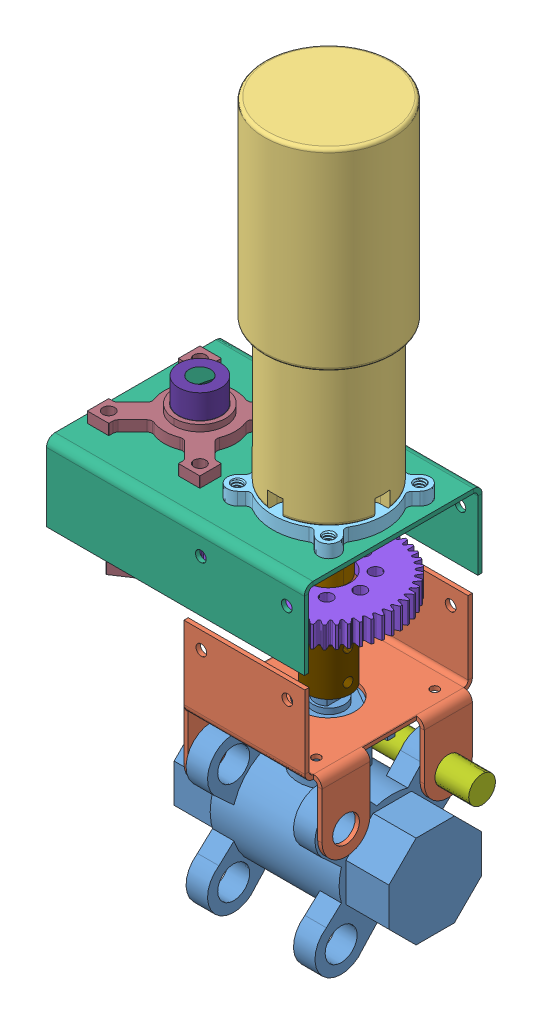
SolidWorks assembly V3 Assembly, configuration Default. Lengths in mm.
Overall size (161.11 207.52 132.19).
34 component instances, 18 part files, 39 mates.
Components (placement in the parent):
- Sharpe 39036-1: Sharpe 39036 [Default] at (-57.1499 -3.3368 16.1541) size (63.5 64.02 45.72)
- Base-sheetmetal-2: Base-sheetmetal [Default] at (-38.0085 26.79 16.1541) x (1 0 0) z (0 0 -1) size (40.82 46.26 49.53)
- Motor_12VDC_638263-1: Motor_12VDC_638263 [Default] at (-38.0997 79.427 15.8703) x (0 0 1) z (1 0 0) size (38 101.9 38)
- Motor_12VDC_638263_shaft-1: Motor_12VDC_638263_shaft [Default] at (-38.0999 79.427 15.8701) x (-0.162768 0 0.986664) z (0.986664 0 0.162768) size (6 16.2 6)
- 555174-1: 555174 [Default] at (-38.0999 82.427 15.8701) x (0 0 -1) z (-1 0 0) size (33.02 4.05 33.02)
- Top-sheetmetal-V3-1: Top-sheetmetal-V3 [Default] at (-57.1499 77.347 15.8701) x (-1 0 0) z (0 0 1) size (76.2 22.86 52.58)
- Sharpe 39036 Bolt-1: Sharpe 39036 Bolt [Default] at (-63.4999 11.7762 1.0411) size (55.88 14.66 12.7)
- 615190 - spur gear-1: 615190 - spur gear [Default] at (-38.0999 60.052 15.8701) x (-0.674102 0 -0.738638) z (0 -1 0) size (39.69 39.69 6.35)
- 625106 assembly.STEP-1: 625106 assembly.STEP [Default] at (-27.8125 48.8438 87.7833) x (-0.17668 0 0.984268) z (-0.984268 0 -0.17668) size (10.67 19.05 10.67)
  - 625106.STEP-1: 625106.STEP [Default] at (-68.9644 10.3754 22.8311) size (10.67 19.05 10.67)
  - 632134_91375A436.STEP-1: 632134_91375A436.STEP [Default] at (-68.9644 13.8044 26.9749) x (-0.895963 0.444129 0) z (0 0 1) size (4.83 4.83 3.18)
  - 632134_91375A436.STEP-2: 632134_91375A436.STEP [Default] at (-68.9644 25.9964 26.9749) x (-0.28947 0.957187 0) z (0 0 1) size (4.83 4.83 3.18)
- 545588 assembly-1: 545588 assembly [Default] at (50.7468 28.5299 -12.9854) x (0.998958 0 0.045634) z (-0.045634 0 0.998958) size (100.53 31.16 84.78)
  - 545588 assembly.STEP-1: 545588 assembly.STEP [Default] at origin size (100.53 31.16 84.78)
    - 545588.STEP-1: 545588.STEP [Default] at (-87.4372 18.8221 32.8798) size (20.57 9.53 26.29)
    - 632110_90128A121.STEP-1: 632110_90128A121.STEP [Default] at (-120.7747 24.8546 20.3068) x (0 0 1) z (-1 0 0) size (5.61 5.61 13.03)
- 535110 assembly - Pillow-1: 535110 assembly - Pillow [Default] at (-82.8272 63.3692 -12.4397) size (33.27 5.08 33.27)
  - 535110 assembly - Pillow.STEP-1: 535110 assembly - Pillow.STEP [Default] at origin size (33.27 5.08 33.27)
    - 535110.STEP-1: 535110.STEP [Default] at (6.6273 15.2478 28.3097) size (33.27 5.08 33.27)
    - 535020.STEP-1: 535020.STEP [Default] at (6.6273 17.9338 28.3097) size (12.7 4.76 12.7)
- D-shaft-2in-2: D-shaft-2in [Default] at (-76.1999 40.042 15.8701) x (0.971835 0 0.23566) z (-0.23566 0 0.971835) size (5.71 50.8 6.35)
- D-shaft-125in-1: D-shaft-125in [Default] at (-38.0999 37.827 15.8701) size (5.71 25.4 6.35)
- Set collar .25in-1: Set collar .25in [Default] at (-76.1999 83.697 15.8701) size (12.48 7.15 12.48)
- 545588 assembly-3: 545588 assembly [Default] at (-62.9007 85.224 -76.5934) x (-0.215135 0 -0.976584) z (-0.976584 0 0.215135) size (100.53 31.16 84.78)
  - 545588 assembly.STEP-1: 545588 assembly.STEP [Default] at origin size (100.53 31.16 84.78)
    - 545588.STEP-1: 545588.STEP [Default] at (-87.4372 18.8221 32.8798) size (20.57 9.53 26.29)
    - 632110_90128A121.STEP-1: 632110_90128A121.STEP [Default] at (-120.7747 24.8546 20.3068) x (0 0 1) z (-1 0 0) size (5.61 5.61 13.03)
- 615190 - spur gear-3: 615190 - spur gear [Default] at (-76.1999 53.702 15.8701) x (0.215135 0 0.976584) z (0 1 0) size (39.69 39.69 6.35)
- shaft-adapter-2: shaft-adapter [Default] at (-38.0999 47.352 15.8701) x (-0.995854 0 -0.090967) z (0.090967 0 -0.995854) size (12.7 15.88 12.7)
- 535110 assembly - Pillow-2: 535110 assembly - Pillow [Default] at (-66.1246 67.5148 43.1437) x (0.834361 0 -0.551218) z (-0.551218 0 -0.834361) size (33.27 5.08 33.27)
  - 535110 assembly - Pillow.STEP-1: 535110 assembly - Pillow.STEP [Default] at origin size (33.27 5.08 33.27)
    - 535110.STEP-1: 535110.STEP [Default] at (6.6273 15.2478 28.3097) size (33.27 5.08 33.27)
    - 535020.STEP-1: 535020.STEP [Default] at (6.6273 17.9338 28.3097) size (12.7 4.76 12.7)
- Set collar .25in-2: Set collar .25in [Default] at (-76.1999 40.042 15.8701) size (12.48 7.15 12.48)
Mates (geometry in assembly coordinates):
- Concentric3: concentric: cylinder of Sharpe 39036-1 through (-19.0499 11.7762 31.2671) axis (-1 0 0) radius 4.7307; circle of Base-sheetmetal-2
- Coincident5: coincident: plane of Sharpe 39036-1 through (-57.1499 -3.3368 16.1541) normal (-1 0 0); plane of Base-sheetmetal-2 through (-57.1499 46.3837 16.1541) normal (1 0 0)
- Concentric4: concentric: circle of Sharpe 39036-1; circle of Base-sheetmetal-2
- Coincident6: coincident: plane of Motor_12VDC_638263-1 through (-38.0997 79.427 15.8703) normal (0 -1 0); plane of Motor_12VDC_638263_shaft-1 through (-38.0999 79.427 15.8701) normal (0 1 0)
- Concentric5: concentric: circle of Motor_12VDC_638263-1; circle of Motor_12VDC_638263_shaft-1
- Concentric6: concentric: cylinder of Sharpe 39036-1 through (-38.0999 23.222 15.8701) axis (0 -1 0) radius 9.0805; cylinder of Motor_12VDC_638263_shaft-1 through (-38.0999 63.227 15.8701) axis (0 1 0) radius 3
- Coincident12: coincident: plane of Motor_12VDC_638263-1 through (-38.0997 82.427 15.8703) normal (0 -1 0); plane of 555174-1 through (-38.0999 82.427 15.8701) normal (0 1 0)
- Concentric7: concentric: cylinder of Motor_12VDC_638263-1 through (-38.0997 124.227 15.8703) axis (0 -1 0) radius 16; cylinder of 555174-1 through (-38.0999 82.427 15.8701) axis (0 1 0) radius 10.033
- Coincident13: coincident: circle of Motor_12VDC_638263-1; cylinder of 555174-1 through (-47.292 81.157 6.6779) axis (0 -1 0) radius 1.5
- Coincident17: coincident: plane of Base-sheetmetal-2 through (-58.4199 46.3837 16.1541) normal (-1 0 0); plane of Sharpe 39036 Bolt-1 through (-58.4199 11.7762 1.0411) normal (1 0 0)
- Concentric15: concentric: cylinder of Sharpe 39036-1 through (-50.7999 11.7762 1.0411) axis (-1 0 0) radius 4.7307; cylinder of Sharpe 39036 Bolt-1 through (-7.6199 11.7762 1.0411) axis (-1 0 0) radius 3.9688
- Concentric18: concentric: cylinder of Motor_12VDC_638263_shaft-1 through (-38.0999 63.227 15.8701) axis (0 1 0) radius 3; cylinder of 625106 assembly.STEP-1/625106.STEP-1 through (-38.0999 78.2692 15.8701) axis (0 -1 0) radius 5.334
- Concentric21: concentric: cylinder of 615190 - spur gear-1 through (-45.323 60.052 22.4621) axis (0 -1 0) radius 1.778; circle of 545588 assembly-1/545588 assembly.STEP-1/545588.STEP-1
- Coincident25: coincident: plane of 615190 - spur gear-1 through (-38.0999 56.877 15.8701) normal (0 -1 0); plane of 545588 assembly-1/545588 assembly.STEP-1/545588.STEP-1 through (-38.0999 56.877 15.8701) normal (0 1 0)
- Concentric25: concentric: cylinder of Motor_12VDC_638263-1 through (-38.0997 124.227 15.8703) axis (0 -1 0) radius 16; circle of Top-sheetmetal-V3-1
- Concentric26: concentric: circle of 555174-1; cylinder of Top-sheetmetal-V3-1 through (-24.6295 78.617 29.3405) axis (0 -1 0) radius 1.651
- Parallel1: parallel: plane of Base-sheetmetal-2 through (-38.0085 26.79 40.9191) normal (0 0 1); plane of Top-sheetmetal-V3-1 through (-57.1499 77.347 42.1591) normal (0 0 1)
- Coincident27: coincident: plane of 555174-1 through (-38.0999 78.617 15.8701) normal (0 -1 0); plane of Top-sheetmetal-V3-1 through (-57.1499 78.617 15.8701) normal (0 1 0)
- Coincident28: coincident: plane of Top-sheetmetal-V3-1 through (-57.1499 78.617 15.8701) normal (0 1 0); plane of 535110 assembly - Pillow-1/535110 assembly - Pillow.STEP-1/535110.STEP-1 through (-76.1999 78.617 15.8701) normal (0 -1 0)
- Concentric27: concentric: cylinder of Top-sheetmetal-V3-1 through (-62.7295 79.887 29.3405) axis (0 -1 0) radius 1.651; cylinder of 535110 assembly - Pillow-1/535110 assembly - Pillow.STEP-1/535110.STEP-1 through (-62.7295 81.792 29.3405) axis (0 1 0) radius 1.778
- Concentric28: concentric: circle of Top-sheetmetal-V3-1; circle of 535110 assembly - Pillow-1/535110 assembly - Pillow.STEP-1/535110.STEP-1
- Concentric29: concentric: cylinder of 535110 assembly - Pillow-1/535110 assembly - Pillow.STEP-1/535020.STEP-1 through (-76.1999 83.6843 15.8701) axis (0 -1 0) radius 3.175; cylinder of D-shaft-2in-2 through (-76.1999 90.842 15.8701) axis (0 -1 0) radius 3.175
- Concentric30: concentric: cylinder of 625106 assembly.STEP-1/625106.STEP-1 through (-38.0999 78.2692 15.8701) axis (0 1 0) radius 3; cylinder of D-shaft-125in-1 through (-38.0999 63.227 15.8701) axis (0 -1 0) radius 3.175
- Coincident29: coincident: plane of Motor_12VDC_638263_shaft-1 through (-38.0999 63.227 15.8701) normal (0 -1 0); plane of D-shaft-125in-1 through (-38.0999 63.227 15.8701) normal (0 1 0)
- Coincident30: coincident: plane of Sharpe 39036-1 through (-38.0999 37.827 15.8701) normal (0 1 0); plane of D-shaft-125in-1 through (-38.0999 37.827 15.8701) normal (0 -1 0)
- Coincident31: coincident: plane of D-shaft-2in-2 through (-76.1999 90.842 15.8701) normal (0 1 0); plane of Set collar .25in-1 through (-76.1999 90.842 15.8701) normal (0 1 0)
- Concentric31: concentric: cylinder of D-shaft-2in-2 through (-76.1999 90.842 15.8701) axis (0 -1 0) radius 3.175; cylinder of Set collar .25in-1 through (-76.1999 90.842 15.8701) axis (0 -1 0) radius 3.175
- Coincident32: coincident: plane of 535110 assembly - Pillow-1/535110 assembly - Pillow.STEP-1/535110.STEP-1 through (-76.1999 83.697 15.8701) normal (0 1 0); plane of Set collar .25in-1 through (-76.1999 83.697 15.8701) normal (0 -1 0)
- Concentric35: concentric: cylinder of 545588 assembly-3/545588 assembly.STEP-1/545588.STEP-1 through (-76.1999 66.402 15.8701) axis (0 1 0) radius 3.175; cylinder of D-shaft-2in-2 through (-76.1999 90.842 15.8701) axis (0 -1 0) radius 3.175
- Coincident34: coincident: plane of 545588 assembly-3/545588 assembly.STEP-1/545588.STEP-1 through (-76.1999 56.877 15.8701) normal (0 -1 0); plane of 615190 - spur gear-3 through (-76.1999 56.877 15.8701) normal (0 1 0)
- Concentric36: concentric: circle of 615190 - spur gear-3; cylinder of D-shaft-2in-2 through (-76.1999 90.842 15.8701) axis (0 -1 0) radius 3.175
- Concentric37: concentric: circle of 545588 assembly-3/545588 assembly.STEP-1/545588.STEP-1; cylinder of 615190 - spur gear-3 through (-84.4403 53.702 10.6048) axis (0 1 0) radius 1.778
- Coincident35: coincident: plane of 615190 - spur gear-1 through (-23.419 53.702 3.1206) normal (0 -1 0); plane of 615190 - spur gear-3 through (-57.3198 53.702 11.2203) normal (0 -1 0)
- Concentric38: concentric: cylinder of D-shaft-125in-1 through (-38.0999 63.227 15.8701) axis (0 -1 0) radius 3.175; cylinder of shaft-adapter-2 through (-38.0999 37.827 15.8701) axis (0 1 0) radius 3.1
- Coincident38: coincident: plane of Sharpe 39036-1 through (-38.0999 37.827 15.8701) normal (0 1 0); circle of shaft-adapter-2
- Concentric39: concentric: cylinder of D-shaft-2in-2 through (-76.1999 90.842 15.8701) axis (0 -1 0) radius 3.175; cylinder of 535110 assembly - Pillow-2/535110 assembly - Pillow.STEP-1/535020.STEP-1 through (-76.1999 47.1997 15.8701) axis (0 1 0) radius 3.175
- Concentric40: concentric: cylinder of D-shaft-2in-2 through (-76.1999 90.842 15.8701) axis (0 -1 0) radius 3.175; cylinder of Set collar .25in-2 through (-76.1999 47.187 15.8701) axis (0 -1 0) radius 3.175
- Coincident39: coincident: plane of D-shaft-2in-2 through (-76.1999 40.042 15.8701) normal (0 -1 0); plane of Set collar .25in-2 through (-76.1999 40.042 15.8701) normal (0 -1 0)
- Coincident40: coincident: plane of 535110 assembly - Pillow-2/535110 assembly - Pillow.STEP-1/535110.STEP-1 through (-76.1999 47.187 15.8701) normal (0 -1 0); plane of Set collar .25in-2 through (-76.1999 47.187 15.8701) normal (0 1 0)
